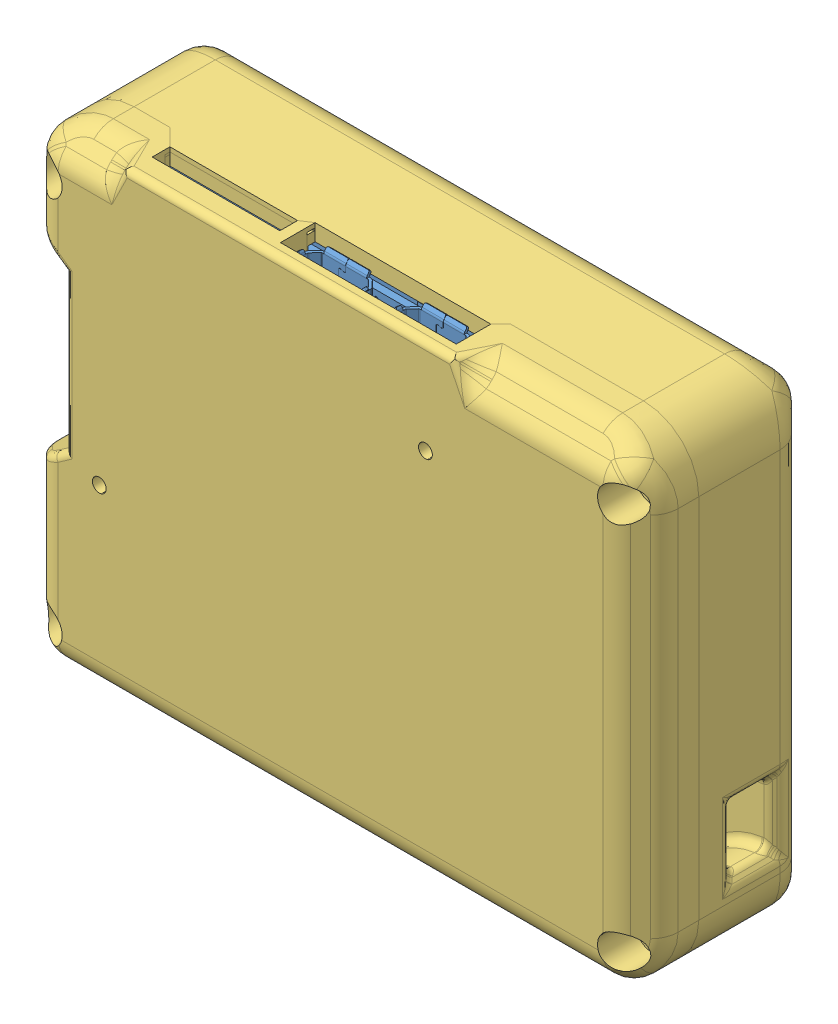
SolidWorks assembly DigitalCase_Assembly, configuration Default. Lengths in mm.
Overall size (71.11 54.84 22.14).
3 component instances, 3 part files, 6 mates.
Components (placement in the parent):
- OSP_Carrier_V5-1: OSP_Carrier_V5 [Default] at origin size (60.4 53.39 11.57)
- SONY NP-BX1-1: SONY NP-BX1 [Default] at (44.7966 -16.7271 -9.328) x (0.001617 0.999999 0) z (0 0 1) size (29.5 43 9)
- Part1^DigitalCase_Assembly-1: Part1^DigitalCase_Assembly [Default] at origin size (71.11 54.84 20.4) (virtual)
Mates (geometry in assembly coordinates):
- Distance1: distance = 1.5 mm: plane of OSP_Carrier_V5-1 through (2 0 -3.328) normal (0 0 -1); plane of SONY NP-BX1-1 through (1.7801 -26.9076 -4.828) normal (0 0 1)
- Coincident1: coordinate: point of ?
- InPlace1: in place: plane of ? through (4 -50 0) normal (0 0 1); plane of ? through (0 0 0) normal (0 0 1); moOrthogonalPlaneRef_w of ? through (4 -50 0) normal (0 0 1); plane of ? through (0 0 0) normal (0 1 0); plane of ? through (4 -50 0) normal (0 0 1); plane of ? through (0 0 0) normal (1 0 0); plane of ? through (4 -50 0) normal (0 0 1); unknown of ?
- Coincident2: coincident: plane of OSP_Carrier_V5-1; plane of Part1^DigitalCase_Assembly-1
- Coincident3: coincident: moOrthogonalPlaneRef_w of OSP_Carrier_V5-1 through (0 0 0) normal (0 1 0); plane of Part1^DigitalCase_Assembly-1 through (0 0 0) normal (0 1 0)
- Coincident4: coincident: moOrthogonalPlaneRef_w of OSP_Carrier_V5-1 through (0 0 0) normal (-1 0 0); plane of Part1^DigitalCase_Assembly-1 through (0 0 0) normal (1 0 0)
